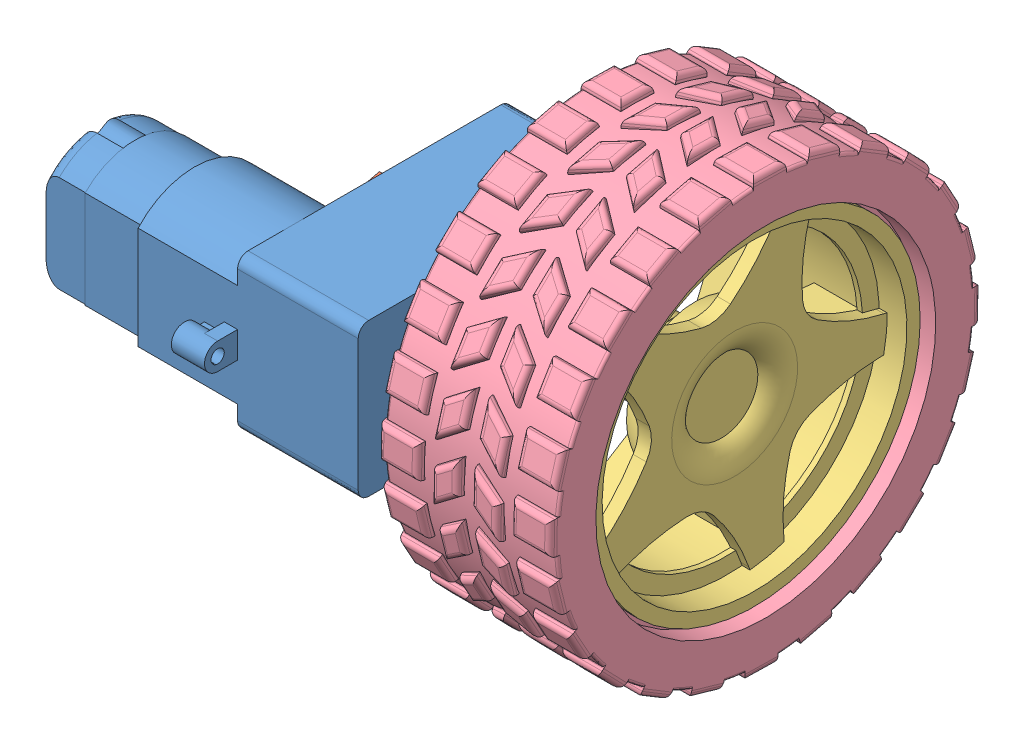
SolidWorks assembly Motoreductor, configuration Predeterminado. Lengths in mm.
Overall size (80.39 78.67 78.67).
5 component instances, 4 part files, 5 mates.
Components (placement in the parent):
- Motor_Rector-1: Motor_Rector [Predeterminado] at (20.7727 6.2871 0) size (49.96 23 46.3)
- Eje_Motor-1: Eje_Motor [Predeterminado] at (-7.4273 6.2871 -9.15) x (1 0 0) z (0 0.239392 -0.970923) size (36.2 5 5)
- Rueda_Completa-1: Rueda_Completa [Predeterminado] at (44.126 10.6724 -8.0688) x (1 0 0) z (0 0.239392 -0.970923) size (31.72 65 65)
  - Rueda-1: Rueda [Predeterminado] at (-23.3533 4.5166 0) size (30 50 50)
  - Llanta-1: Llanta [Predeterminado] at (-17.6533 4.5166 0) size (26.05 65 65)
Mates (geometry in assembly coordinates):
- Paralelo1: parallel anti-aligned: plane of Eje_Motor-1 through (20.7727 8.3643 -11.3088) normal (0 0.970923 0.239392); plane of Rueda_Completa-1/Rueda-1 through (34.7727 8.2289 -8.6712) normal (0 -0.970923 -0.239392)
- Concéntrica3: concentric aligned: cylinder of Eje_Motor-1 through (28.7727 6.2871 -9.15) axis (-1 0 0) radius 2.5; cylinder of Rueda_Completa-1/Rueda-1 through (34.7727 6.2871 -9.15) axis (-1 0 0) radius 3
- Concéntrica4: concentric anti-aligned: cylinder of Motor_Rector-1 through (2.5717 6.2871 -9.15) axis (1 0 0) radius 2.5; cylinder of Eje_Motor-1 through (28.7727 6.2871 -9.15) axis (-1 0 0) radius 2.5
- Coincidente5: coincident aligned: plane of Motor_Rector-1 through (20.7727 6.2871 0) normal (1 0 0); plane of Eje_Motor-1 through (20.7727 6.2871 -9.15) normal (1 0 0)
- Coincidente6: coincident anti-aligned: plane of Motor_Rector-1 through (20.7727 6.2871 0) normal (1 0 0); plane of Rueda_Completa-1/Rueda-1 through (20.7727 6.2871 -9.15) normal (-1 0 0)
